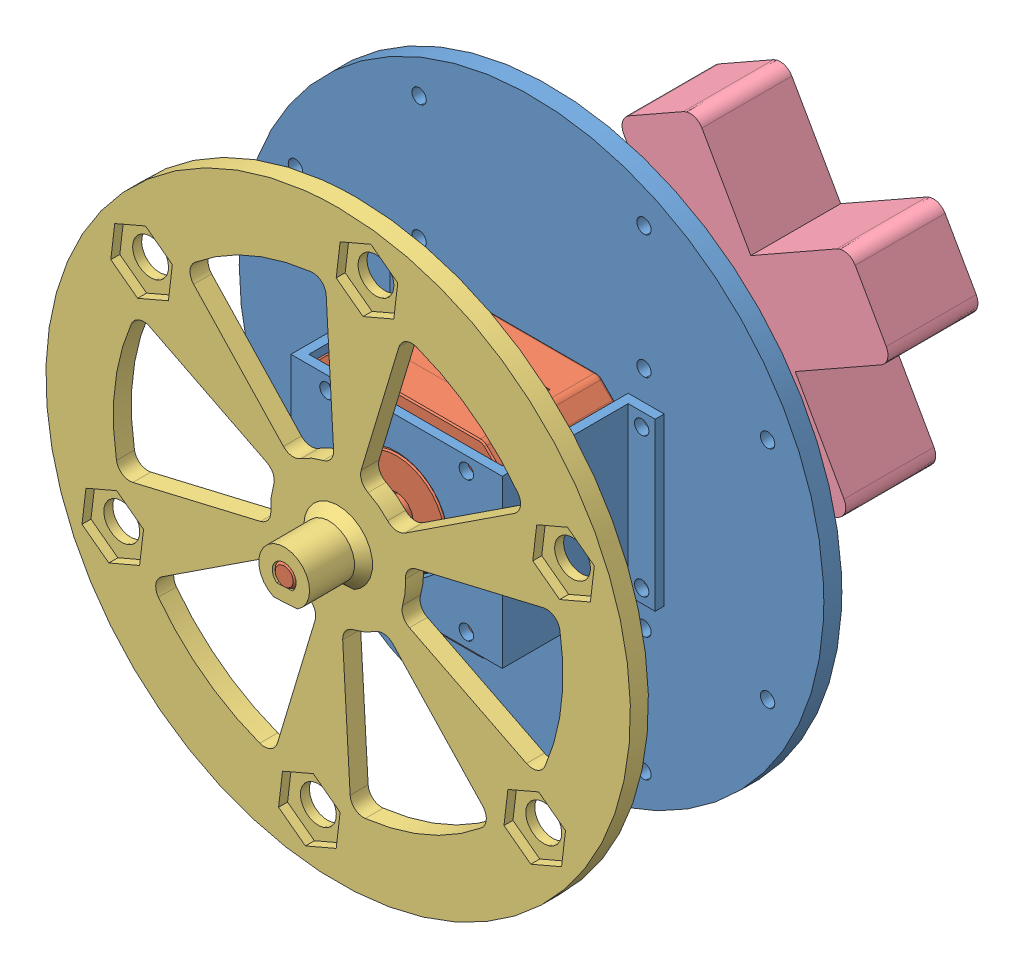
SolidWorks assembly RW_Assembly, configuration Défaut. Lengths in mm.
Overall size (137.17 137.17 120).
7 component instances, 6 part files, 13 mates.
Components (placement in the parent):
- RW_Satellite-1: RW_Satellite [Défaut] at (-9.5815 6.5873 113.9) size (130 130 59)
- E3D Slimline Stepper Motor 0.9deg V1.1-1: E3D Slimline Stepper Motor 0.9deg V1.1 [Défaut] at (-9.5815 6.5873 120.9) x (1 0 0) z (0 -1 0) size (42 53 47.1)
- RW_Flywheel-1: RW_Flywheel [Défaut] at (-9.5815 6.5873 156.9) x (-0.056793 0.998386 0) z (0 0 1) size (130 130 16)
- RW_Base-1: RW_Base [Défaut] at (25.7926 15.1705 72.9) x (-0.869632 -0.4937 0) z (0 0 -1) size (70 70 20)
- 8mm Bearing SKF 608 (RS 286-7530)-1: 8mm Bearing SKF 608 (RS 286-7530) [Default] at (-9.5815 6.5873 89.9) x (0 0 -1) z (1 0 0) size (7 22 22)
- 8mm Bearing SKF 608 (RS 286-7530)-2: 8mm Bearing SKF 608 (RS 286-7530) [Default] at (-9.5815 6.5873 96.9) x (0 0 -1) z (1 0 0) size (7 22 22)
- 8mm_threaded_rod-1: 8mm_threaded_rod [Défaut] at (-9.5815 6.5873 52.9) size (8 8 65)
Mates (geometry in assembly coordinates):
- Coïncidente1: coincident anti-aligned: plane of RW_Satellite-1 through (-9.5815 6.5873 145.9) normal (0 0 -1); plane of E3D Slimline Stepper Motor 0.9deg V1.1-1 through (-9.5815 6.5873 145.9) normal (0 0 1)
- Coaxiale1: concentric aligned: cylinder of RW_Satellite-1 through (-25.0815 -8.9127 147.9) axis (0 0 -1) radius 1.6; cylinder of E3D Slimline Stepper Motor 0.9deg V1.1-1 through (-25.0815 -8.9127 145.9) axis (0 0 -1) radius 1.2645
- Coaxiale2: concentric aligned: cylinder of RW_Satellite-1 through (-25.0815 22.0873 147.9) axis (0 0 -1) radius 1.6; cylinder of E3D Slimline Stepper Motor 0.9deg V1.1-1 through (-25.0815 22.0873 145.9) axis (0 0 -1) radius 1.2645
- Coaxiale3: concentric anti-aligned: cylinder of E3D Slimline Stepper Motor 0.9deg V1.1-1 through (-9.5815 6.5873 163.9) axis (0 0 -1) radius 2.5; cylinder of RW_Flywheel-1 through (-9.5815 6.5873 156.9) axis (0 0 1) radius 2.65
- Coïncidente2: coincident aligned: plane of E3D Slimline Stepper Motor 0.9deg V1.1-1 through (-9.5815 6.5873 172.9) normal (0 0 1); plane of RW_Flywheel-1 through (-9.5815 6.5873 172.9) normal (0 0 1)
- Coaxiale4: concentric anti-aligned: cylinder of RW_Satellite-1 through (-9.5815 6.5873 88.9) axis (0 0 1) radius 11.1; cylinder of 8mm Bearing SKF 608 (RS 286-7530)-2 through (-9.5815 6.5873 96.9) axis (0 0 -1) radius 11
- Coïncidente3: coincident anti-aligned: plane of RW_Satellite-1 through (-9.5815 6.5873 103.9) normal (0 0 -1); plane of 8mm Bearing SKF 608 (RS 286-7530)-2 through (-9.5815 15.0923 103.9) normal (0 0 1)
- Coïncidente4: coincident anti-aligned: plane of 8mm Bearing SKF 608 (RS 286-7530)-1 through (-9.5815 15.0923 96.9) normal (0 0 1); plane of 8mm Bearing SKF 608 (RS 286-7530)-2 through (-9.5815 15.0923 96.9) normal (0 0 -1)
- Coaxiale5: concentric anti-aligned: cylinder of RW_Satellite-1 through (-9.5815 6.5873 88.9) axis (0 0 1) radius 11.1; cylinder of 8mm Bearing SKF 608 (RS 286-7530)-1 through (-9.5815 6.5873 89.9) axis (0 0 -1) radius 11
- Coaxiale6: concentric aligned: cylinder of 8mm Bearing SKF 608 (RS 286-7530)-1 through (-9.5815 6.5873 89.9) axis (0 0 -1) radius 4; cylinder of 8mm_threaded_rod-1 through (-9.5815 6.5873 117.9) axis (0 0 -1) radius 4
- Coïncidente5: coincident aligned: plane of RW_Satellite-1 through (-9.5815 6.5873 117.9) normal (0 0 1); plane of 8mm_threaded_rod-1 through (-9.5815 6.5873 117.9) normal (0 0 1)
- Coïncidente6: coincident aligned: plane of RW_Base-1 through (25.7926 15.1705 52.9) normal (0 0 -1); plane of 8mm_threaded_rod-1 through (-9.5815 6.5873 52.9) normal (0 0 -1)
- Coaxiale7: concentric aligned: cylinder of RW_Base-1 through (-9.5815 6.5873 72.901) axis (0 0 -1) radius 4.05; cylinder of 8mm_threaded_rod-1 through (-9.5815 6.5873 117.9) axis (0 0 -1) radius 4
